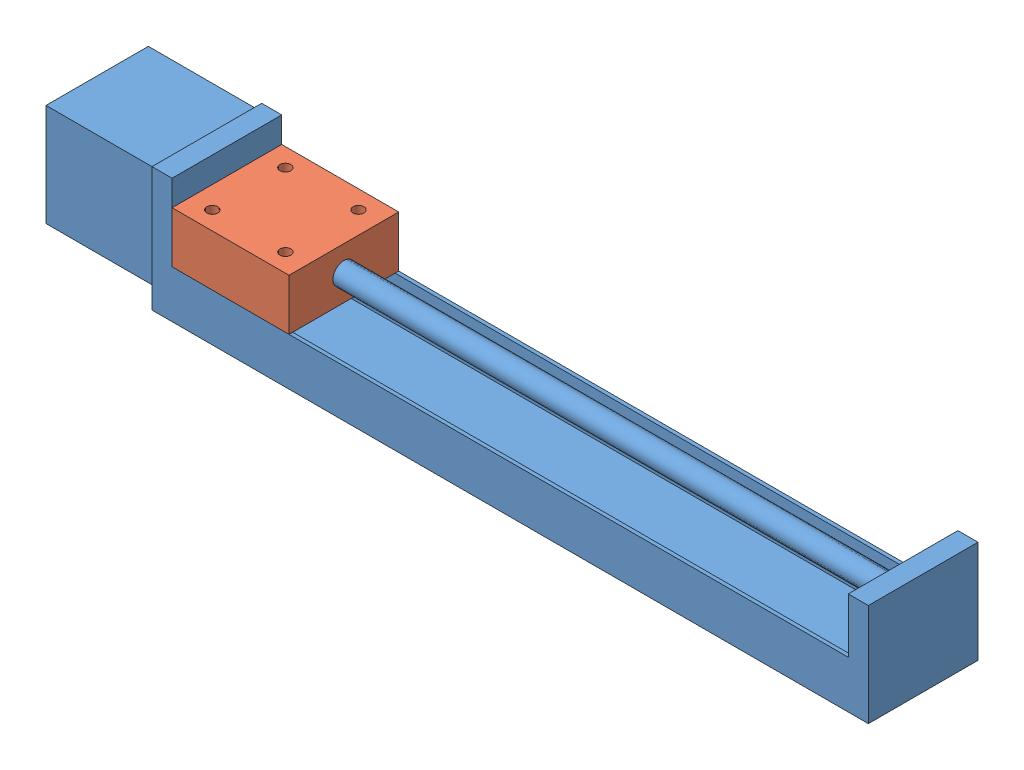
SolidWorks assembly stepper_motor_down, configuration 默认. Lengths in mm.
Overall size (226 34 30).
2 component instances, 2 part files, 3 mates.
Components (placement in the parent):
- base_stepper_motor-1: base_stepper_motor [默认] at (-81.3569 -5.0622 176) size (226 34 30)
- slider-1: slider [默认] at (-44.8569 -11.0622 176) x (1 0 0) z (0 1 0) size (32 30 14)
Mates (geometry in assembly coordinates):
- 同心1: concentric aligned: cylinder of base_stepper_motor-1 through (-69.3422 -4.0622 176) axis (1 0 0) radius 3; cylinder of slider-1 through (-61.8569 -4.0622 176) axis (1 0 0) radius 3
- 平行1: parallel anti-aligned: plane of base_stepper_motor-1 through (124.1431 -23.0622 190) normal (0 1 0); plane of slider-1 through (-44.8569 -11.0622 176) normal (0 -1 0)
- LimitDistance1: limit distance = 0 mm anti-aligned: plane of slider-1 through (-60.8569 2.9378 191) normal (-1 0 0); plane of base_stepper_motor-1 through (-60.8569 -5.0622 176) normal (1 0 0)
